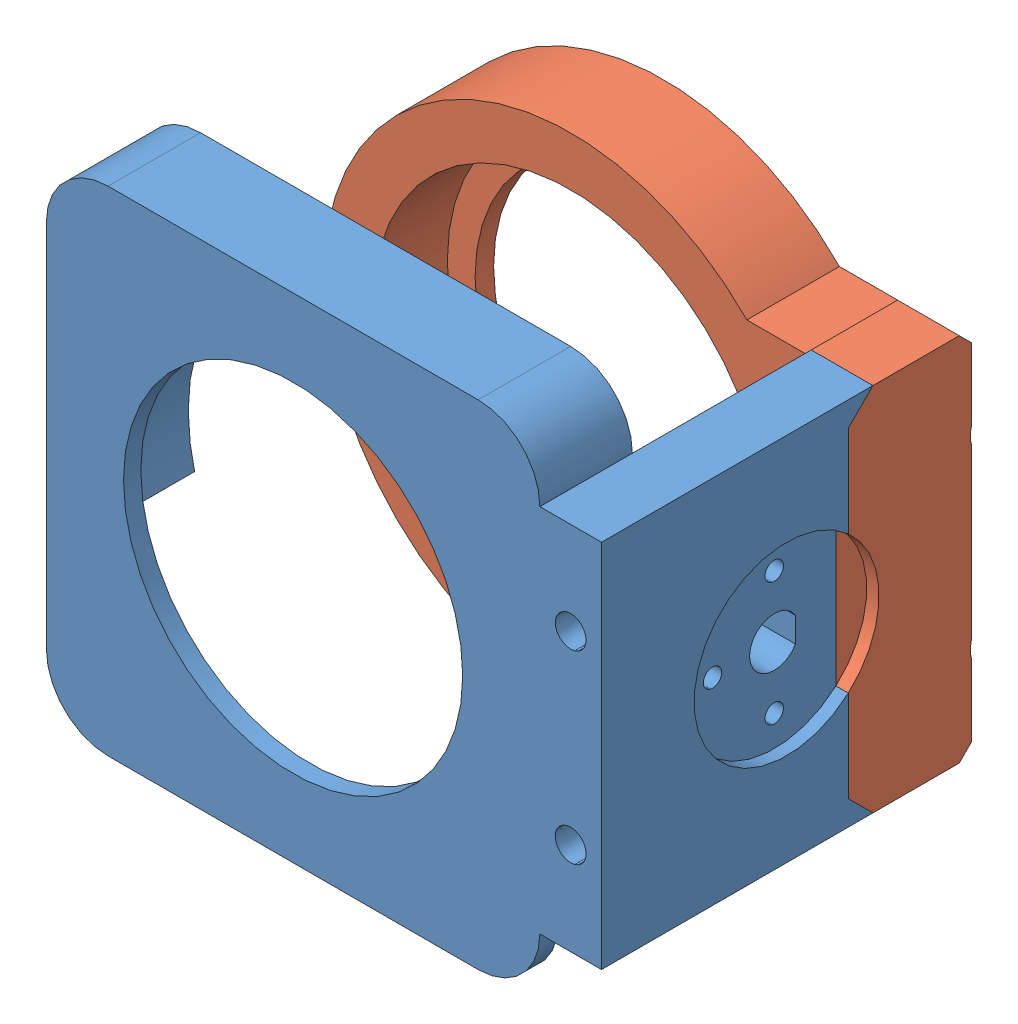
SolidWorks assembly PiVyAxis, configuration Default. Lengths in mm.
Overall size (90 95.96 126.21).
6 component instances, 4 part files, 9 mates.
Components (placement in the parent):
- PiVRing-1: PiVRing [Default] at (-10.1445 32.4522 102.0243) size (90 95.96 109.96)
- 5972K249_Ball Bearing-1: 5972K249_Ball Bearing [5972K249] at (29.8555 72.4522 108.2243) x (0.455975 -0.889993 0) z (0 0 1) size (62 62 12) (hidden)
- PiVRing2-1: PiVRing2 [Default] at (69.8555 32.4522 72.0243) x (-1 0 0) z (0 0 -1) size (90 80 20.25)
- 92010A328_Passivated 18-8 Stainless Steel Phillips Flat Head Screw-1: 92010A328_Passivated 18-8 Stainless Steel Phillips Flat Head Screw [92010A328] at (74.8555 87.4522 67.6243) x (0.998285 -0.05854 0) z (0 0 -1) size (9.2 9.2 20.12)
- 92010A328_Passivated 18-8 Stainless Steel Phillips Flat Head Screw-2: 92010A328_Passivated 18-8 Stainless Steel Phillips Flat Head Screw [92010A328] at (74.8555 57.4522 67.6243) x (1 0 0) z (0 0 -1) size (9.2 9.2 20.12)
- 5972K249_Ball Bearing-2: 5972K249_Ball Bearing [5972K249] at (29.8555 72.4522 66.0243) size (62 62 12) (hidden)
Mates (geometry in assembly coordinates):
- Concentric1: concentric anti-aligned: cylinder of PiVRing-1 through (29.8555 72.4522 117.0243) axis (0 0 -1) radius 32; cylinder of 5972K249_Ball Bearing-1 through (29.8555 72.4522 114.2243) axis (0 0 1) radius 31
- Coincident1: coincident anti-aligned: plane of PiVRing-1 through (29.8555 72.4522 114.2243) normal (0 0 -1); plane of 5972K249_Ball Bearing-1 through (50.594 83.0773 114.2243) normal (0 0 1)
- Coincident2: coincident anti-aligned: plane of PiVRing-1 through (79.8555 102.4522 77.0243) normal (0 0 -1); plane of PiVRing2-1 through (69.8555 32.4522 77.0243) normal (0 0 1)
- Coincident3: coincident aligned: plane of PiVRing-1 through (79.8555 32.4522 102.0243) normal (1 0 0); plane of PiVRing2-1 through (79.8555 102.4522 77.0243) normal (1 0 0)
- Coincident4: coincident anti-aligned: plane of PiVRing-1 through (69.8555 46.4522 77.0243) normal (0 0.707107 -0.707107); plane of PiVRing2-1 through (69.8555 42.4522 73.0243) normal (0 -0.707107 0.707107)
- Coincident5: coincident aligned: cone of PiVRing2-1 through (74.8555 87.4522 57.0243) axis (0 0 1); cone of 92010A328_Passivated 18-8 Stainless Steel Phillips Flat Head Screw-1 through (74.8555 87.4522 60.1243) axis (0 0 1)
- Coincident7: coincident aligned: cone of PiVRing2-1 through (74.8555 57.4522 57.0243) axis (0 0 1); cone of 92010A328_Passivated 18-8 Stainless Steel Phillips Flat Head Screw-2 through (74.8555 57.4522 60.1243) axis (0 0 1)
- Concentric2: concentric anti-aligned: cylinder of PiVRing2-1 through (29.8555 72.4522 72.0243) axis (0 0 -1) radius 32; cylinder of 5972K249_Ball Bearing-2 through (29.8555 72.4522 72.0243) axis (0 0 1) radius 31
- Coincident8: coincident anti-aligned: plane of PiVRing2-1 through (29.8555 72.4522 60.0243) normal (0 0 1); plane of 5972K249_Ball Bearing-2 through (29.8555 93.0517 60.0243) normal (0 0 -1)
